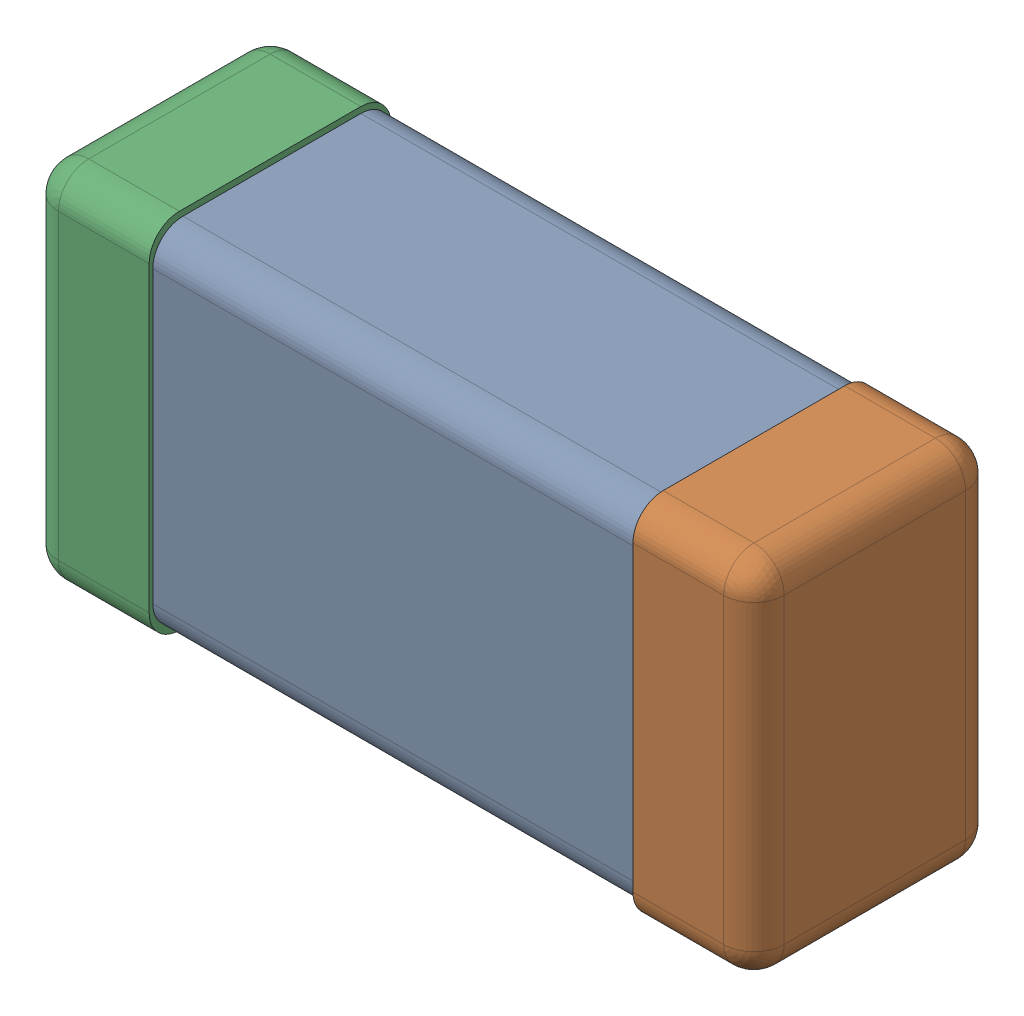
SolidWorks assembly C0201_020_3, configuration Standard. Lengths in mm.
Overall size (0.6 0.3 0.2).
3 component instances, 3 part files, 0 mates.
Components (placement in the parent):
- Part 3_2-1: Part 3_2 [Standard] at (0 0 -7.3015) size (0.5 0.29 0.2)
- Part 2_2-1: Part 2_2 [Standard] at (0 0 -7.3) size (0.1 0.3 0.2)
- Part 1_2-1: Part 1_2 [Standard] at (0 0 -7.3) size (0.1 0.3 0.2)
